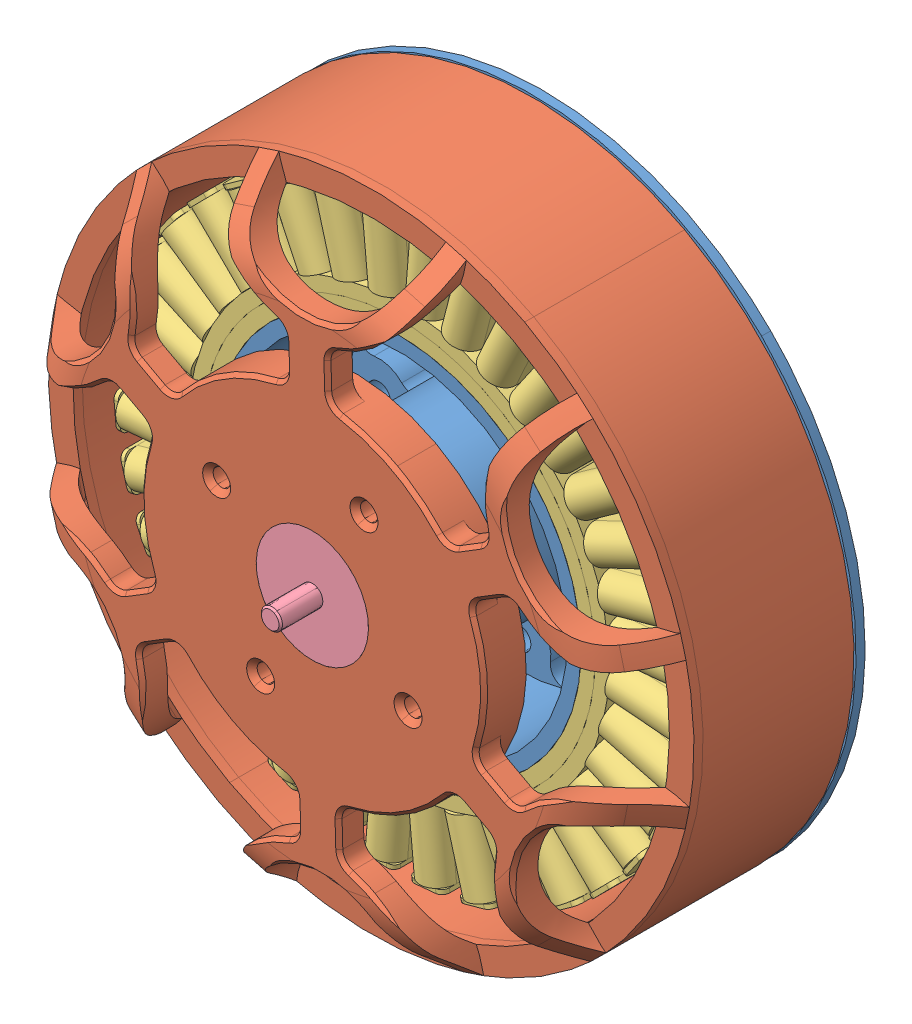
SolidWorks assembly MOTOR 9235, configuration Default. Lengths in mm.
Overall size (130.11 130.11 47.51).
7 component instances, 5 part files, 0 mates.
Components (placement in the parent):
- MOTOR 9235.STEP-1: MOTOR 9235.STEP [Default] at origin size (130.11 130.11 47.51)
  - MOTOR BACK HOUSING REV01.STEP-1: MOTOR BACK HOUSING REV01.STEP [Default] at (0 0 6) x (0.707107 0.707107 0) z (-0.707107 0.707107 0) size (92 25.2 92)
  - MOTOR ROTOR REV01_9235.STEP-1: MOTOR ROTOR REV01_9235.STEP [Default] at (0 0 6.3) x (-0.879859 0.475234 0) z (0.475234 0.879859 0) size (92 31.21 92)
  - MOTOR STATOR REV01.STEP-1: MOTOR STATOR REV01.STEP [Default] at (0 0 7.2) x (-0.996782 0.080159 0) z (0.080159 0.996782 0) size (81.2 19.01 81.2)
  - MOTOR SHAFT REV01_9235.STEP-1: MOTOR SHAFT REV01_9235.STEP [Default] at (0 0 3.5) x (0.879859 -0.475234 0) z (-0.475234 -0.879859 0) size (19.64 47.51 18.94)
  - NMB L2112KK BEARING.STEP-1: NMB L2112KK BEARING.STEP [Default] at (0 0 19.2) x (0.90792 -0.419144 0) z (0 0 1) size (21 21 5)
  - NMB L2112KK BEARING.STEP-2: NMB L2112KK BEARING.STEP [Default] at (0 0 3.5) x (0.889392 -0.457145 0) z (0 0 1) size (21 21 5)
